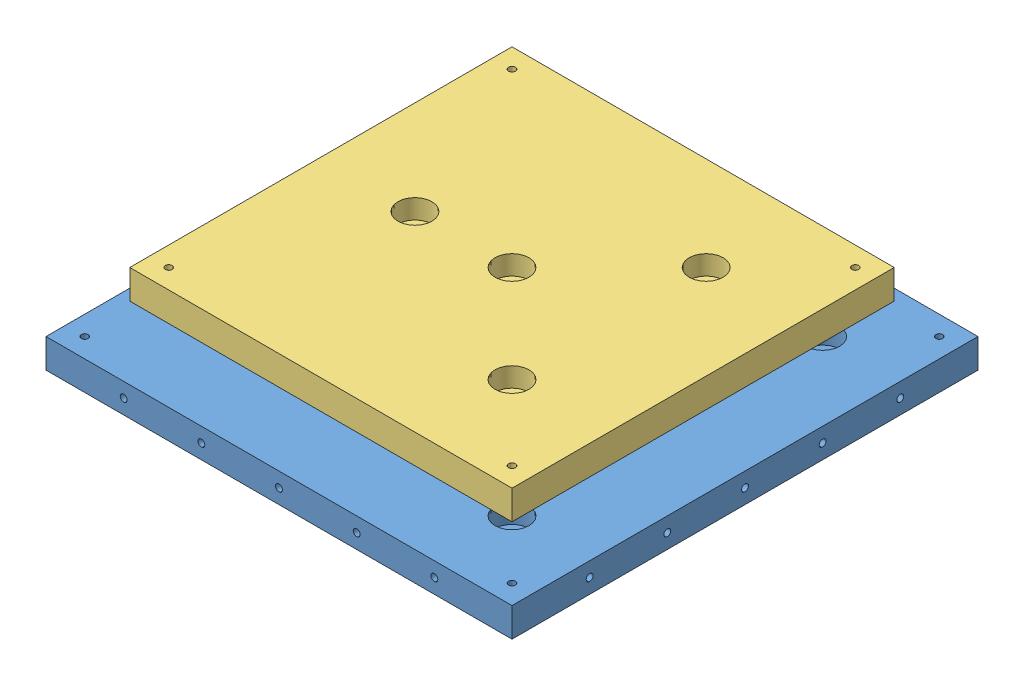
SolidWorks assembly Plate_Assem, configuration Default. Lengths in mm.
Overall size (152.4 40.24 152.4).
8 component instances, 3 part files, 20 mates.
Components (placement in the parent):
- 40K_Plate-1: 40K_Plate [Default] at (-27.6421 -0.0146 11.3607) size (152.4 9.53 152.4)
- Sphere-1: Sphere [Default] at (23.1579 -3.2409 11.3607) x (0.995759 0 0.091998) z (-0.091998 0 0.995759) size (15.68 15.87 15.68)
- Sphere-2: Sphere [Default] at (-78.4421 -3.2407 62.1607) x (0.054769 0 0.998499) z (-0.998499 0 0.054769) size (15.68 15.87 15.68)
- Sphere-3: Sphere [Default] at (-78.4421 -3.2407 -39.3393) x (-0.546566 0 0.837416) z (-0.837416 0 -0.546566) size (15.68 15.87 15.68)
- Sphere-7: Sphere [Default] at (-59.3921 16.3001 43.1107) x (0.311054 0 0.950392) z (0.950392 0 -0.311054) size (15.68 15.87 15.68)
- Sphere-8: Sphere [Default] at (-59.3921 16.3001 -20.3893) x (0.635383 0 0.772197) z (0.772197 0 -0.635383) size (15.68 15.87 15.68)
- Sphere-9: Sphere [Default] at (4.1079 16.3001 11.3607) x (-0.291497 0 -0.956572) z (-0.956572 0 0.291497) size (15.68 15.87 15.68)
- 4K_Plate-1: 4K_Plate [Default] at (-27.6421 19.537 11.3607) size (125 9.53 125)
Mates (geometry in assembly coordinates):
- Concentric1: concentric aligned: circle of 40K_Plate-1; circle of Sphere-2
- Tangent5: tangent anti-aligned: plane of 40K_Plate-1 through (-42.9058 -20.1819 11.3607) normal (-0.603492 -0.797369 0); sphere of Sphere-3
- Tangent6: tangent anti-aligned: plane of 40K_Plate-1 through (-49.3813 28.7086 11.3607) normal (0.603492 -0.797369 0); sphere of Sphere-3
- Tangent8: tangent aligned: cone of 40K_Plate-1 through (-78.4421 6.3354 62.1607) axis (0 1 0); sphere of Sphere-2
- Tangent9: tangent anti-aligned: plane of 40K_Plate-1 through (-27.6421 4.6966 11.3607) normal (0 -1 0); sphere of Sphere-1
- Tangent13: tangent anti-aligned: plane of 40K_Plate-1 through (-27.6421 4.6966 11.3607) normal (0 -1 0); sphere of Sphere-1
- Parallel5: parallel aligned: plane of Sphere-1 through (23.1579 -11.1774 11.3607) normal (0 -1 0); plane of Sphere-2 through (-78.4421 -11.1772 62.1607) normal (0 -1 0)
- Parallel6: parallel aligned: plane of Sphere-2 through (-78.4421 -11.1772 62.1607) normal (0 -1 0); plane of Sphere-3 through (-78.4421 -11.1772 -39.3393) normal (0 -1 0)
- Distance1: distance = 3.9688 mm anti-aligned: plane of 40K_Plate-1 through (-27.6421 -0.0146 -27.533) normal (0 0 -1); cylinder of Sphere-3 through (-78.4421 4.6968 -39.3393) axis (0 1 0) radius 7.8375
- Distance2: distance = 1.6875 mm anti-aligned: cylinder of Sphere-1 through (23.1579 4.6966 11.3607) axis (0 1 0) radius 7.8375; plane of 40K_Plate-1 through (13.6329 4.6966 20.8857) normal (0 0 -1)
- Distance4: distance = 1.6875 mm anti-aligned: plane of 40K_Plate-1 through (32.6829 4.6966 1.8357) normal (-1 0 0); cylinder of Sphere-1 through (23.1579 4.6966 11.3607) axis (0 1 0) radius 7.8375
- Tangent22: tangent aligned: cone of 40K_Plate-1 through (-59.3921 8.3354 43.1107) axis (0 -1 0); sphere of Sphere-7
- Concentric12: concentric aligned: circle of 40K_Plate-1; cylinder of Sphere-7 through (-59.3921 8.3626 43.1107) axis (0 -1 0) radius 7.8375
- Tangent23: tangent aligned: cone of 40K_Plate-1 through (-59.3921 8.3354 -20.3893) axis (0 -1 0); sphere of Sphere-8
- Concentric13: concentric aligned: circle of 40K_Plate-1; circle of Sphere-8
- Concentric14: concentric anti-aligned: circle of 40K_Plate-1; circle of Sphere-9
- Tangent24: tangent aligned: cone of 40K_Plate-1 through (4.1079 8.3354 11.3607) axis (0 -1 0); sphere of Sphere-9
- Distance5: distance = 13.7 mm aligned: plane of 4K_Plate_COPIED-1 through (-27.6421 29.062 73.8607) normal (0 0 1); plane of 40K_Plate-1 through (-27.6421 9.5104 87.5607) normal (0 0 1)
- Distance6: distance = 13.7 mm aligned: plane of 4K_Plate_COPIED-1 through (-90.1421 29.062 11.3607) normal (-1 0 0); plane of 40K_Plate-1 through (-103.8421 9.5104 11.3607) normal (-1 0 0)
- Tangent25: tangent anti-aligned: face of Sphere-7
